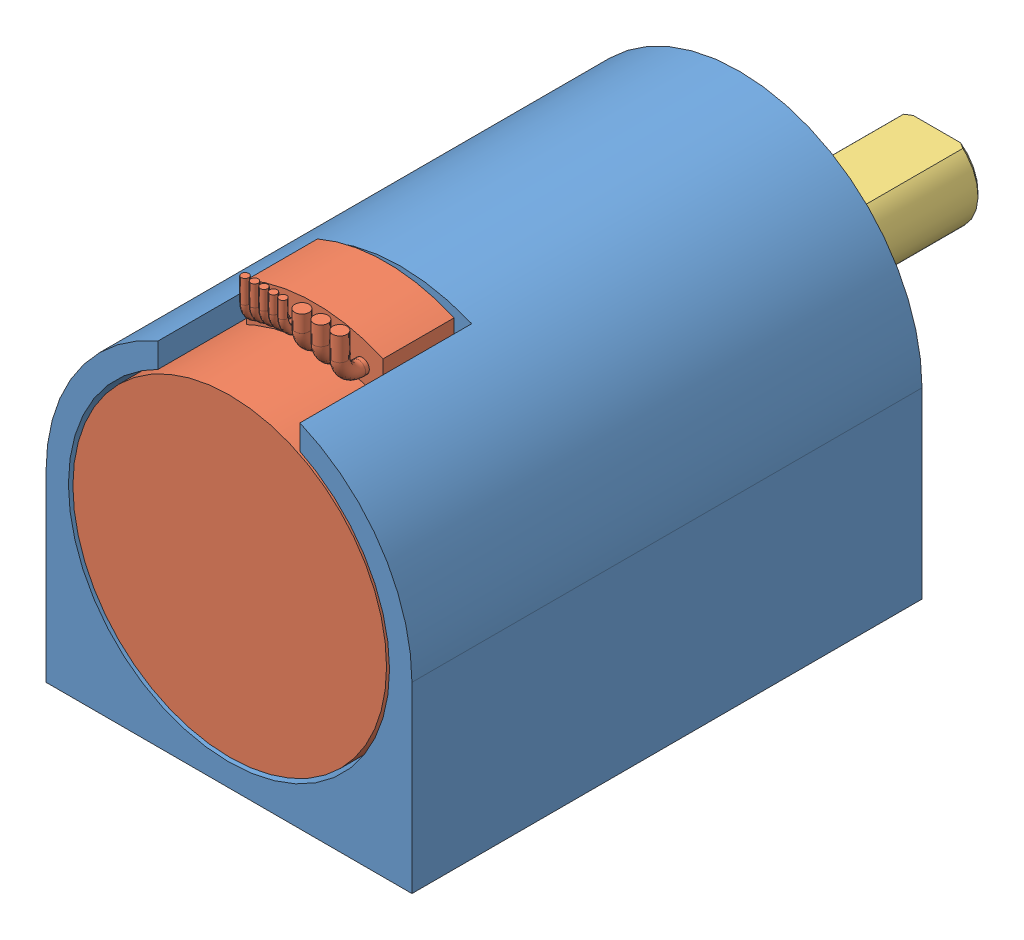
SolidWorks assembly Assemblage moteur-cache-insert Total, configuration Défaut. Lengths in mm.
Overall size (49 52 94.8).
8 component instances, 4 part files, 11 mates.
Components (placement in the parent):
- Cache moteur_V2-1: Cache moteur_V2 [Défaut] at (5.7936 10.0699 68.3) size (49 49 68.3)
- Assemblage Moteur-réducteur Faulhaber-1: Assemblage Moteur-réducteur Faulhaber [Défaut] at (10.0724 13.6207 164.5) x (1 0 0) z (0 0 -1) size (42 48.5 94.7)
  - 4221G_BXTH _ moteur-1: 4221G_BXTH _ moteur [Défaut] at (-4.2788 3.5509 53) size (42 48.5 35)
  - 42gpt-2stage_standard+KSx _ reducteur-1: 42gpt-2stage_standard+KSx _ reducteur [Défaut] at (-138.2788 3.5509 53) size (42 42.04 72.7)
- Insert M4-1: Insert M4 [Défaut] at (-13.7064 -14.4301 123.6) x (1 0 0) z (0 1 0) size (7 7 8)
- Insert M4-2: Insert M4 [Défaut] at (25.2936 -14.4301 123.6) x (-0.837169 0 -0.546944) z (0 1 0) size (7 7 8)
- Insert M4-3: Insert M4 [Défaut] at (25.2936 -14.4301 75.3) x (1 0 0) z (0 1 0) size (7 7 8)
- Insert M4-4: Insert M4 [Défaut] at (-13.7064 -14.4301 75.3) x (-0.837169 0 -0.546944) z (0 1 0) size (7 7 8)
Mates (geometry in assembly coordinates):
- Coaxiale1: concentric aligned: circle of Cache moteur_V2-1; circle of Insert M4-1
- Coaxiale2: concentric aligned: circle of Cache moteur_V2-1; circle of Insert M4-2
- Coaxiale3: concentric aligned: circle of Cache moteur_V2-1; circle of Insert M4-3
- Coaxiale4: concentric aligned: circle of Cache moteur_V2-1; circle of Insert M4-4
- Coïncidente11: coincident aligned: plane of Cache moteur_V2-1 through (5.7936 -14.4301 133.6) normal (0 -1 0); plane of Insert M4-1 through (-13.7064 -14.4301 123.6) normal (0 -1 0)
- Coïncidente12: coincident aligned: plane of Cache moteur_V2-1 through (5.7936 -14.4301 133.6) normal (0 -1 0); plane of Insert M4-2 through (25.2936 -14.4301 123.6) normal (0 -1 0)
- Coïncidente13: coincident aligned: plane of Cache moteur_V2-1 through (5.7936 -14.4301 133.6) normal (0 -1 0); plane of Insert M4-3 through (25.2936 -14.4301 75.3) normal (0 -1 0)
- Coïncidente14: coincident aligned: plane of Cache moteur_V2-1 through (5.7936 -14.4301 133.6) normal (0 -1 0); plane of Insert M4-4 through (-13.7064 -14.4301 75.3) normal (0 -1 0)
- Coaxiale5: concentric anti-aligned: circle of Cache moteur_V2-1; circle of Assemblage Moteur-réducteur Faulhaber-1/42gpt-2stage_standard+KSx _ reducteur-1
- Coïncidente15: coincident anti-aligned: plane of Cache moteur_V2-1 through (5.7936 10.0699 68.3) normal (0 0 1); plane of Assemblage Moteur-réducteur Faulhaber-1/42gpt-2stage_standard+KSx _ reducteur-1 through (5.7936 10.0699 68.3) normal (0 0 -1)
- Coaxiale6: concentric anti-aligned: circle of Cache moteur_V2-1; circle of Assemblage Moteur-réducteur Faulhaber-1/42gpt-2stage_standard+KSx _ reducteur-1
